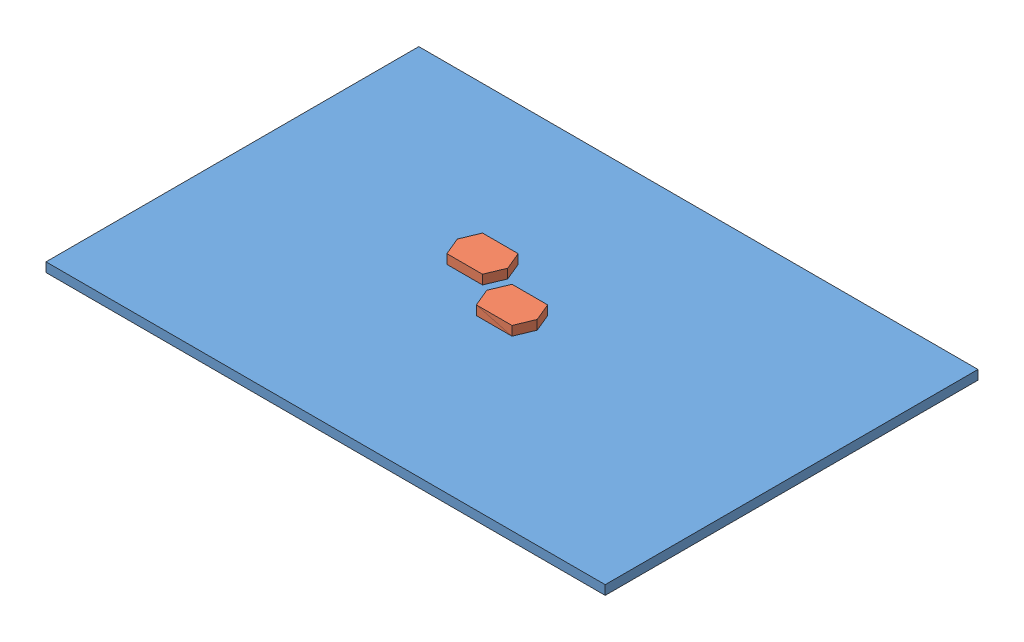
SolidWorks assembly two_node_2250, configuration Default. Lengths in mm.
Overall size (600 25 400).
3 component instances, 2 part files, 6 mates.
Components (placement in the parent):
- ground-1: ground [Default] at origin size (600 10 400)
- node_2250-1: node_2250 [Default] at origin size (54.12 10 38.27)
- node_2250-2: node_2250 [Default] at (-58.4287 5 -26.7912) size (54.12 10 38.27)
Mates (geometry in assembly coordinates):
- Coincident1: coincident aligned: plane of ground-1 through (0 0 0) normal (0 0 1)
- Coincident2: coincident aligned: plane of ground-1 through (0 0 0) normal (0 1 0)
- Coincident3: coincident aligned: plane of ground-1 through (0 0 0) normal (1 0 0)
- Coincident4: coincident aligned: plane of node_2250-1 through (0 0 0) normal (0 0 1)
- Coincident5: coincident aligned: plane of node_2250-1 through (0 0 0) normal (0 1 0)
- Coincident6: coincident aligned: plane of node_2250-1 through (0 0 0) normal (1 0 0)
